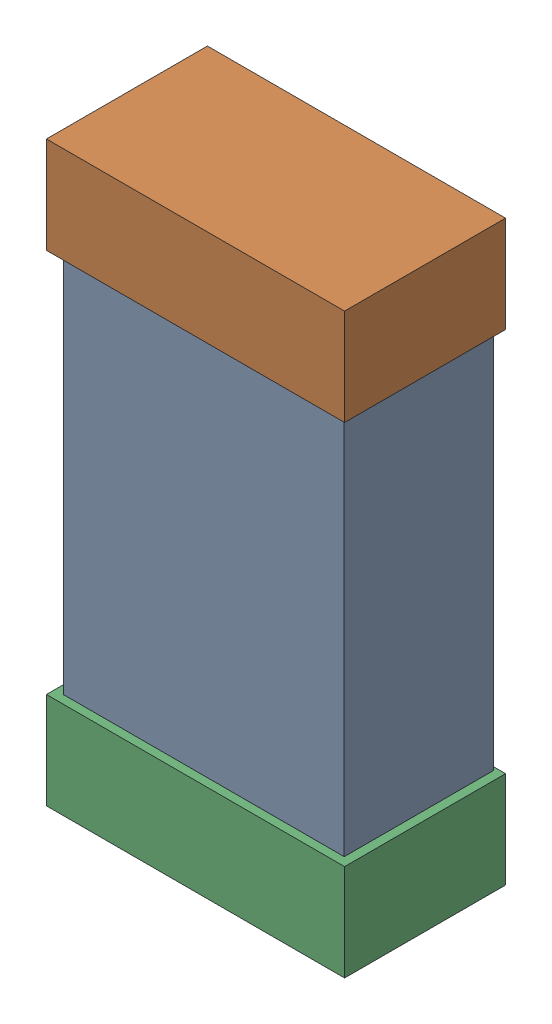
SolidWorks assembly C21, configuration Default. Lengths in mm.
Overall size (0.85 1.65 0.46).
6 component instances, 2 part files, 0 mates.
Components (placement in the parent):
- 432124816_2-1: 432124816_2 [Default] at (39.9166 30.3991 -0.8615) size (0.8 1.5 0.42)
  - Extruded (1)-1: Extruded (1) [Default] at origin size (0.8 1.5 0.42)
- 432138512_4-1: 432138512_4 [Default] at (39.9166 31.0849 -0.8715) size (0.85 0.28 0.46)
  - Extruded-1: Extruded [Default] at origin size (0.85 0.28 0.46)
- 432138512_5-1: 432138512_5 [Default] at (39.9166 29.7134 -0.8715) size (0.85 0.28 0.46)
  - Extruded-1: Extruded [Default] at origin size (0.85 0.28 0.46)
